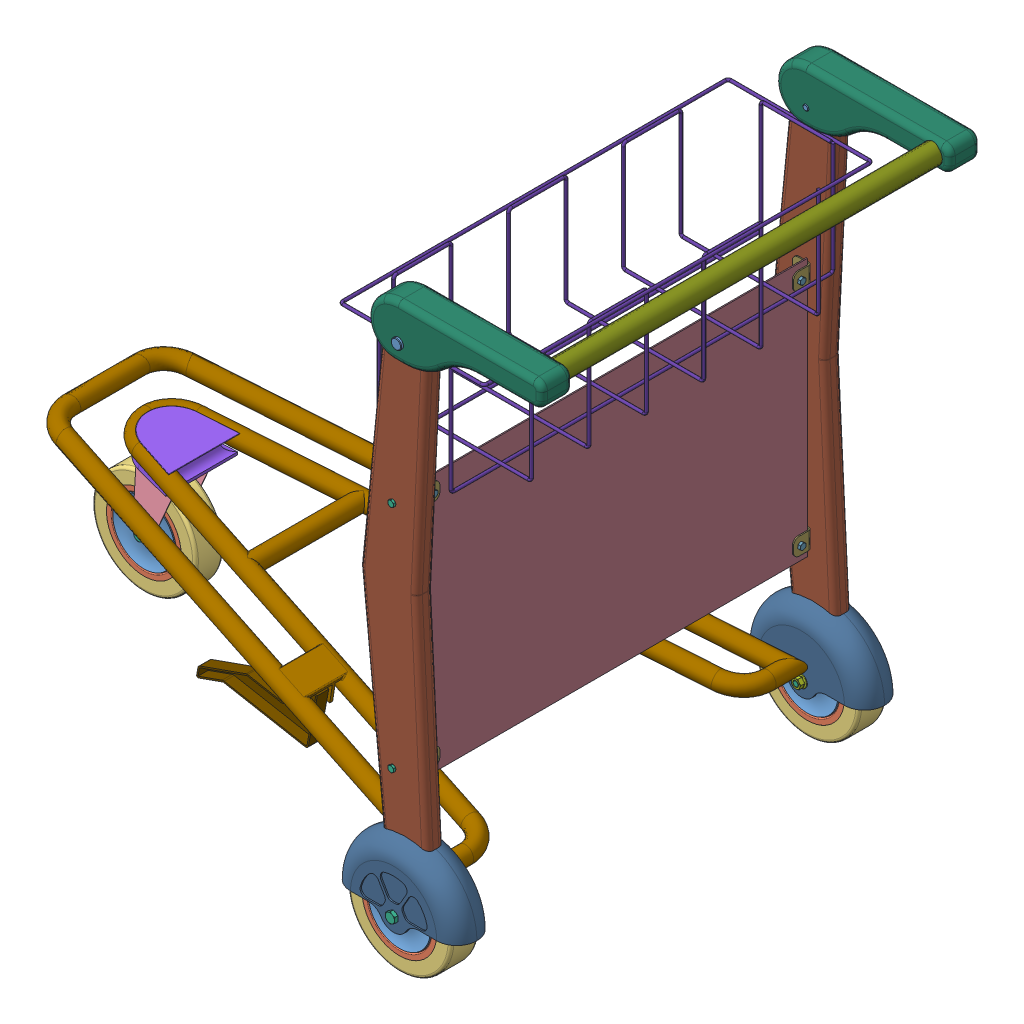
SolidWorks assembly Airport Trolley, configuration Default. Lengths in mm.
Overall size (1159.66 1012.5 792.8).
66 component instances, 19 part files, 94 mates.
Components (placement in the parent):
- Castor With Bracket-1: Castor With Bracket [Default] at origin size (180 254.25 124.91)
  - Castor Wheel-1: Castor Wheel [Default] at origin size (180 180 79.3)
    - Inside 2-1: Inside 2 [Default] at origin size (110.08 110.08 79.3)
    - Inside 1-1: Inside 1 [Default] at origin size (130 130 50)
    - Rubber Wheel-2: Rubber Wheel [Default] at (0 45 25) x (0 0 1) z (-1 0 0) size (50 180 180)
  - Castor Bracket-1: Castor Bracket [Default] at (-10.2542 104.2118 25) x (0 0 -1) z (-0.060111 -0.998192 0) size (56.48 71.04 113.41)
  - Bracket Top-1: Bracket Top [Default] at (28.7861 104.684 17.6727) x (0.060111 0.998192 0) z (0 0 1) size (15 52 52)
  - hex bolt gradeab_iso-1: hex bolt gradeab_iso [ISO 4014 - M10 x 70 x 26-C] at (0 0 59.6369) x (0 0 -1) z (1 0 0) size (76.4 18.48 16)
  - hex flange nut gradea_iso-2: hex flange nut gradea_iso [Hexagon Flange Nut ISO - 4161 - M10 - N] at (0 0 -13.2369) x (0.923728 0.383049 0) z (0 0 -1) size (21.8 21.8 10)
  - Rubber Top-1: Rubber Top [Default] at (80.9125 134.2079 90) x (-0.989154 0.146881 0) z (0 0 -1) size (106.47 44.76 124.91)
- Luggage Frame-2: Luggage Frame [Default<As Machined>] at (793.1035 28.4538 320) x (-0.989154 0.146881 0) z (0 0 -1) size (942.05 35.85 636.5)
- Back Wheel-2: Back Wheel [Default] at (795 0 350) size (220 200 86.4)
  - Castor Wheel-1: Castor Wheel [Default] at origin size (180 180 79.3)
    - Inside 2-1: Inside 2 [Default] at origin size (110.08 110.08 79.3)
    - Inside 1-1: Inside 1 [Default] at origin size (130 130 50)
    - Rubber Wheel-2: Rubber Wheel [Default] at (0 45 25) x (0 0 1) z (-1 0 0) size (50 180 180)
  - Wheel Casing-1: Wheel Casing [Default] at (0 0 -10) size (220 135 70)
  - hex bolt gradeab_iso-1: hex bolt gradeab_iso [ISO 4014 - M10 x 80 x 26-C] at (0 0 66.4) x (0 0 -1) z (1 0 0) size (86.4 18.48 16)
  - hex flange nut gradea_iso-1: hex flange nut gradea_iso [Hexagon Flange Nut ISO - 4161 - M10 - N] at (0 0 -20) x (0.923728 0.383049 0) z (0 0 -1) size (21.8 21.8 10)
- Back Wheel-3: Back Wheel [Default] at (795 0 -310) x (-1 0 0) z (0 0 -1) size (220 200 86.4)
  - Castor Wheel-1: Castor Wheel [Default] at origin size (180 180 79.3)
    - Inside 2-1: Inside 2 [Default] at origin size (110.08 110.08 79.3)
    - Inside 1-1: Inside 1 [Default] at origin size (130 130 50)
    - Rubber Wheel-2: Rubber Wheel [Default] at (0 45 25) x (0 0 1) z (-1 0 0) size (50 180 180)
  - Wheel Casing-1: Wheel Casing [Default] at (0 0 -10) size (220 135 70)
  - hex bolt gradeab_iso-1: hex bolt gradeab_iso [ISO 4014 - M10 x 80 x 26-C] at (0 0 66.4) x (0 0 -1) z (1 0 0) size (86.4 18.48 16)
  - hex flange nut gradea_iso-1: hex flange nut gradea_iso [Hexagon Flange Nut ISO - 4161 - M10 - N] at (0 0 -20) x (0.923728 0.383049 0) z (0 0 -1) size (21.8 21.8 10)
- Support-1: Support [Right] at (835 80 -320) x (-1 0 0) z (0 0 -1) size (119.95 779.01 31.28)
- Support-3: Support [Left] at (835 80 390) x (-1 0 0) z (0 0 -1) size (119.95 779.01 31.28)
- 'L' Bracket-1: 'L' Bracket [Default] at (791.3545 602.9093 -320) x (1 0 0) z (0 -1 0) size (32.07 32.07 30)
- 'L' Bracket-2: 'L' Bracket [Default] at (791.3545 202.9093 -320) x (1 0 0) z (0 -1 0) size (32.07 32.07 30)
- 'L' Bracket-3: 'L' Bracket [Default] at (791.3545 602.9093 360) x (1 0 0) z (0 1 0) size (32.07 32.07 30)
- 'L' Bracket-4: 'L' Bracket [Default] at (791.3545 202.9093 360) x (1 0 0) z (0 1 0) size (32.07 32.07 30)
- Advert Board-2: Advert Board [Default] at (789.4275 402.9093 20) x (0 0 -1) z (1 0 0) size (668 450 2)
- hex bolt gradeab_iso-7: hex bolt gradeab_iso [ISO 4014 - M6 x 40 x 18-N] at (773.8545 602.9093 394) x (0 0 -1) z (1 0 0) size (44 11.55 10)
- hex bolt gradeab_iso-8: hex bolt gradeab_iso [ISO 4014 - M6 x 40 x 18-N] at (773.8545 202.9093 394) x (0 0 -1) z (1 0 0) size (44 11.55 10)
- hex bolt gradeab_iso-9: hex bolt gradeab_iso [ISO 4014 - M6 x 40 x 18-N] at (773.8545 202.9093 -354) x (0 0 1) z (-1 0 0) size (44 11.55 10)
- hex bolt gradeab_iso-10: hex bolt gradeab_iso [ISO 4014 - M6 x 40 x 18-N] at (773.8545 602.9093 -354) x (0 0 1) z (-1 0 0) size (44 11.55 10)
- hex flange nut gradea_iso-2: hex flange nut gradea_iso [Hexagon Flange Nut ISO - 4161 - M6 - N] at (773.8545 602.9093 352) x (0.923728 0.383049 0) z (0 0 -1) size (14.2 14.2 6)
- hex flange nut gradea_iso-3: hex flange nut gradea_iso [Hexagon Flange Nut ISO - 4161 - M6 - N] at (773.8545 202.9093 352) x (0.923728 0.383049 0) z (0 0 -1) size (14.2 14.2 6)
- hex flange nut gradea_iso-4: hex flange nut gradea_iso [Hexagon Flange Nut ISO - 4161 - M6 - N] at (773.8545 202.9093 -312) size (14.2 14.2 6)
- hex flange nut gradea_iso-5: hex flange nut gradea_iso [Hexagon Flange Nut ISO - 4161 - M6 - N] at (773.8545 602.9093 -312) size (14.2 14.2 6)
- hex screw gradec_iso-1: hex screw gradec_iso [ISO 4018 - M6 x 12-NN] at (797.8025 602.9093 -300.427) x (-1 0 0) z (0 0.924225 0.381849) size (16.38 11.55 10)
- hex screw gradec_iso-2: hex screw gradec_iso [ISO 4018 - M6 x 12-NN] at (797.8025 602.9093 340.427) x (-1 0 0) z (0 0.924225 0.381849) size (16.38 11.55 10)
- hex screw gradec_iso-3: hex screw gradec_iso [ISO 4018 - M6 x 12-NN] at (797.8025 202.9093 340.427) x (-1 0 0) z (0 0.924225 0.381849) size (16.38 11.55 10)
- hex screw gradec_iso-4: hex screw gradec_iso [ISO 4018 - M6 x 12-NN] at (797.8025 202.9093 -300.427) x (-1 0 0) z (0 0.924225 0.381849) size (16.38 11.55 10)
- hex flange nut gradea_iso-6: hex flange nut gradea_iso [Hexagon Flange Nut ISO - 4161 - M6 - N] at (783.4275 602.9093 340.427) x (0 0 1) z (-1 0 0) size (14.2 14.2 6)
- hex flange nut gradea_iso-7: hex flange nut gradea_iso [Hexagon Flange Nut ISO - 4161 - M6 - N] at (783.4275 602.9093 -300.427) x (0 0 1) z (-1 0 0) size (14.2 14.2 6)
- hex flange nut gradea_iso-8: hex flange nut gradea_iso [Hexagon Flange Nut ISO - 4161 - M6 - N] at (783.4275 202.9093 -300.427) x (0 0 1) z (-1 0 0) size (14.2 14.2 6)
- hex flange nut gradea_iso-9: hex flange nut gradea_iso [Hexagon Flange Nut ISO - 4161 - M6 - N] at (783.4275 202.9093 340.427) x (0 0 1) z (-1 0 0) size (14.2 14.2 6)
- Handle-1: Handle [Right] at (795.0187 860 -308) x (-1 0 0) z (0 0 -1) size (303.42 93.75 54)
- Handle-3: Handle [Left] at (795.0187 860 402) x (-1 0 0) z (0 0 -1) size (303.42 93.75 54)
- Handle Bar-1: Handle Bar [Default] at (1015.0187 900.625 20) size (34 34 744)
- Basket-1: Basket [Default] at (775 826 20) x (0 0 1) z (-1 0 0) size (680 200 255)
- Lock-1: Lock [Right] at (472.1076 75.5835 -160) x (-0.983426 0.181312 0) z (0 0 -1) size (193.3 113.17 20)
- Lock-2: Lock [Left] at (472.1076 75.5835 220) x (-0.983426 0.181312 0) z (0 0 -1) size (193.3 113.17 20)
- clevis pin headed_iso-1: clevis pin headed_iso [Clevis Pin ISO 2341 - B - 10 x 55 - St] at (795.0187 860 -366) x (0 0 1) z (-1 0 0) size (59 18 18)
- clevis pin headed_iso-2: clevis pin headed_iso [Clevis Pin ISO 2341 - B - 10 x 55 - St] at (795.0187 860 406) x (0 0 -1) z (1 0 0) size (59 18 18)
- hex screw gradec_iso-5: hex screw gradec_iso [ISO 4018 - M5 x 12-NC] at (455.5431 68.4689 -166.375) x (0 0 1) z (-1 0 0) size (15.88 9.24 8)
- hex screw gradec_iso-6: hex screw gradec_iso [ISO 4018 - M5 x 12-NC] at (435.8746 72.0951 -166.375) x (0 0 1) z (-1 0 0) size (15.88 9.24 8)
- hex screw gradec_iso-7: hex screw gradec_iso [ISO 4018 - M5 x 12-NC] at (455.5431 68.4689 206.375) x (0 0 -1) z (1 0 0) size (15.88 9.24 8)
- hex screw gradec_iso-8: hex screw gradec_iso [ISO 4018 - M5 x 12-NC] at (435.8746 72.0951 206.375) x (0 0 -1) z (1 0 0) size (15.88 9.24 8)
- hex flange nut gradea_iso-10: hex flange nut gradea_iso [Hexagon Flange Nut ISO - 4161 - M5 - C] at (435.8746 72.0951 -150) size (11.8 11.8 5)
- hex flange nut gradea_iso-11: hex flange nut gradea_iso [Hexagon Flange Nut ISO - 4161 - M5 - C] at (455.5431 68.4689 -150) size (11.8 11.8 5)
- hex flange nut gradea_iso-12: hex flange nut gradea_iso [Hexagon Flange Nut ISO - 4161 - M5 - C] at (435.76 71.4065 190) x (0.923728 0.383049 0) z (0 0 -1) size (11.8 11.8 5)
- hex flange nut gradea_iso-13: hex flange nut gradea_iso [Hexagon Flange Nut ISO - 4161 - M5 - C] at (455.5431 68.4689 190) x (0.923728 0.383049 0) z (0 0 -1) size (11.8 11.8 5)
Mates (geometry in assembly coordinates):
- Coincident7: coincident: plane of Castor With Bracket-1/Rubber Top-1 through (80.9125 134.2079 90) normal (0.146881 0.989154 0); plane of Luggage Frame-2 through (793.1035 28.4538 320) normal (0.146881 0.989154 0)
- Distance9: distance = 720 mm: plane of Castor With Bracket-1/Rubber Top-1 through (80.9125 134.2079 90) normal (-0.989154 0.146881 0); plane of Luggage Frame-2 through (793.1035 28.4538 320) normal (-0.989154 0.146881 0)
- Distance10: distance = 230 mm: plane of Castor With Bracket-1/Rubber Top-1 through (80.9125 134.2079 90) normal (0 0 -1); plane of Luggage Frame-2 through (793.1035 28.4538 320) normal (0 0 -1)
- Distance12: distance = 350 mm: plane of ? through (0 0 0) normal (0 0 1); plane of ? through (795 0 350) normal (0 0 1)
- Coincident12: coincident: plane of ? through (0 0 0) normal (0 1 0); plane of ? through (795 0 350) normal (0 1 0)
- Distance11: distance = 795 mm: plane of ? through (0 0 0) normal (1 0 0); plane of ? through (795 0 350) normal (1 0 0)
- Distance14: distance = 310 mm: plane of ? through (0 0 0) normal (0 0 1); plane of ? through (795 0 -310) normal (0 0 -1)
- Coincident15: coincident: plane of ? through (0 0 0) normal (0 1 0); plane of ? through (795 0 -310) normal (0 1 0)
- Distance13: distance = 795 mm: plane of ? through (0 0 0) normal (1 0 0); plane of ? through (795 0 -310) normal (-1 0 0)
- Distance15: distance = 10 mm: plane of ? through (795 0 -310) normal (0 0 -1); plane of Support-1 through (835 80 -320) normal (0 0 -1)
- Distance16: distance = 80 mm: plane of ? through (795 0 -310) normal (0 1 0); plane of Support-1 through (835 80 -320) normal (0 1 0)
- Distance17: distance = 40 mm: plane of ? through (795 0 -310) normal (-1 0 0); plane of Support-1 through (835 80 -320) normal (-1 0 0)
- Distance21: distance = 40 mm: plane of ? through (795 0 350) normal (0 0 1); plane of Support-3 through (835 80 390) normal (0 0 -1)
- Distance22: distance = 80 mm: plane of ? through (795 0 350) normal (0 1 0); plane of Support-3 through (835 80 390) normal (0 1 0)
- Distance23: distance = 40 mm: plane of ? through (795 0 350) normal (1 0 0); plane of Support-3 through (835 80 390) normal (-1 0 0)
- Coincident19: coincident: cylinder of Support-1 through (773.8545 602.9093 -350.6717) axis (0 0 1) radius 3; circle of 'L' Bracket-1
- Coincident20: coincident: plane of Support-1 through (835 80 -320) normal (0 0 1); plane of 'L' Bracket-1 through (771.3545 607.9093 -320) normal (0 0 -1)
- Coincident23: coincident: cylinder of Support-1 through (773.8545 202.9093 -350.6717) axis (0 0 1) radius 3; circle of 'L' Bracket-2
- Coincident24: coincident: plane of Support-1 through (835 80 -320) normal (0 0 1); plane of 'L' Bracket-2 through (771.3545 207.9093 -320) normal (0 0 -1)
- Coincident25: coincident: cylinder of Support-3 through (773.8545 602.9093 390.6095) axis (0 0 -1) radius 3; circle of 'L' Bracket-3
- Coincident26: coincident: plane of Support-3 through (835 80 360) normal (0 0 -1); plane of 'L' Bracket-3 through (771.3545 597.9093 360) normal (0 0 1)
- Coincident27: coincident: cylinder of Support-3 through (773.8545 202.9093 390.6095) axis (0 0 -1) radius 3; circle of 'L' Bracket-4
- Coincident28: coincident: plane of Support-3 through (835 80 360) normal (0 0 -1); plane of 'L' Bracket-4 through (771.3545 197.9093 360) normal (0 0 1)
- Coincident33: coincident: plane of Advert Board-2 through (791.4275 627.9093 354) normal (1 0 0); plane of 'L' Bracket-3 through (791.4275 597.9093 377.927) normal (-1 0 0)
- Distance24: distance = 4 mm: plane of 'L' Bracket-3 through (771.3545 597.9093 358) normal (0 0 -1); plane of Advert Board-2 through (791.4275 177.9093 354) normal (0 0 1)
- Distance25: distance = 10 mm: plane of 'L' Bracket-3 through (791.4275 617.9093 377.927) normal (0 1 0); plane of Advert Board-2 through (791.4275 627.9093 -314) normal (0 1 0)
- Concentric6: concentric: cylinder of Support-3 through (773.8545 602.9093 390.6095) axis (0 0 -1) radius 3; cylinder of hex bolt gradeab_iso-7 through (773.8545 602.9093 394) axis (0 0 1) radius 5
- Coincident41: coincident: plane of Support-3 through (835 80 390) normal (0 0 1); plane of hex bolt gradeab_iso-7 through (773.8545 608.6828 390) normal (0 0 -1)
- Concentric7: concentric: cylinder of Support-3 through (773.8545 202.9093 390.6095) axis (0 0 -1) radius 3; cylinder of hex bolt gradeab_iso-8 through (773.8545 202.9093 394) axis (0 0 1) radius 5
- Coincident42: coincident: plane of Support-3 through (835 80 390) normal (0 0 1); plane of hex bolt gradeab_iso-8 through (773.8545 208.6828 390) normal (0 0 -1)
- Concentric8: concentric: cylinder of Support-1 through (773.8545 202.9093 -350.6717) axis (0 0 1) radius 3; cylinder of hex bolt gradeab_iso-9 through (773.8545 202.9093 -354) axis (0 0 -1) radius 5
- Coincident43: coincident: plane of Support-1 through (835 80 -350) normal (0 0 -1); plane of hex bolt gradeab_iso-9 through (773.8545 208.6828 -350) normal (0 0 1)
- Concentric9: concentric: cylinder of Support-1 through (773.8545 602.9093 -350.6717) axis (0 0 1) radius 3; cylinder of hex bolt gradeab_iso-10 through (773.8545 602.9093 -354) axis (0 0 -1) radius 5
- Coincident44: coincident: plane of Support-1 through (835 80 -350) normal (0 0 -1); plane of hex bolt gradeab_iso-10 through (773.8545 608.6828 -350) normal (0 0 1)
- Concentric10: concentric: cylinder of 'L' Bracket-3 through (773.8545 602.9093 358) axis (0 0 -1) radius 3; cylinder of hex flange nut gradea_iso-2 through (773.8545 602.9093 377.0375) axis (0 0 -1) radius 3
- Coincident45: coincident: plane of 'L' Bracket-3 through (771.3545 597.9093 358) normal (0 0 -1); plane of hex flange nut gradea_iso-2 through (776.0661 597.5762 358) normal (0 0 1)
- Concentric11: concentric: cylinder of 'L' Bracket-4 through (773.8545 202.9093 358) axis (0 0 -1) radius 3; cylinder of hex flange nut gradea_iso-3 through (773.8545 202.9093 377.0375) axis (0 0 -1) radius 3
- Coincident46: coincident: plane of 'L' Bracket-4 through (771.3545 197.9093 358) normal (0 0 -1); plane of hex flange nut gradea_iso-3 through (776.0661 197.5762 358) normal (0 0 1)
- Concentric12: concentric: cylinder of 'L' Bracket-2 through (773.8545 202.9093 -318) axis (0 0 1) radius 3; cylinder of hex flange nut gradea_iso-4 through (773.8545 202.9093 -337.0375) axis (0 0 1) radius 3
- Coincident47: coincident: plane of 'L' Bracket-2 through (771.3545 207.9093 -318) normal (0 0 1); plane of hex flange nut gradea_iso-4 through (773.8545 208.6828 -318) normal (0 0 -1)
- Concentric13: concentric: cylinder of 'L' Bracket-1 through (773.8545 602.9093 -318) axis (0 0 1) radius 3; cylinder of hex flange nut gradea_iso-5 through (773.8545 602.9093 -337.0375) axis (0 0 1) radius 3
- Coincident48: coincident: plane of 'L' Bracket-1 through (771.3545 607.9093 -318) normal (0 0 1); plane of hex flange nut gradea_iso-5 through (773.8545 608.6828 -318) normal (0 0 -1)
- Concentric14: concentric: cylinder of 'L' Bracket-1 through (791.4275 602.9093 -300.427) axis (-1 0 0) radius 3; cylinder of hex screw gradec_iso-1 through (797.8025 602.9093 -300.427) axis (1 0 0) radius 3
- Coincident49: coincident: plane of 'L' Bracket-1 through (793.4275 607.9093 -337.927) normal (1 0 0); plane of hex screw gradec_iso-1 through (793.4275 600.7047 -295.091) normal (-1 0 0)
- Concentric15: concentric: cylinder of 'L' Bracket-3 through (791.4275 602.9093 340.427) axis (-1 0 0) radius 3; cylinder of hex screw gradec_iso-2 through (797.8025 602.9093 340.427) axis (1 0 0) radius 3
- Coincident50: coincident: plane of 'L' Bracket-3 through (793.4275 597.9093 377.927) normal (1 0 0); plane of hex screw gradec_iso-2 through (793.4275 600.7047 345.763) normal (-1 0 0)
- Concentric16: concentric: cylinder of 'L' Bracket-4 through (791.4275 202.9093 340.427) axis (-1 0 0) radius 3; cylinder of hex screw gradec_iso-3 through (797.8025 202.9093 340.427) axis (1 0 0) radius 3
- Coincident51: coincident: plane of 'L' Bracket-4 through (793.4275 197.9093 377.927) normal (1 0 0); plane of hex screw gradec_iso-3 through (793.4275 200.7047 345.763) normal (-1 0 0)
- Concentric171: concentric: cylinder of 'L' Bracket-2 through (791.4275 202.9093 -300.427) axis (-1 0 0) radius 3; cylinder of hex screw gradec_iso-4 through (797.8025 202.9093 -300.427) axis (1 0 0) radius 3
- Coincident521: coincident: plane of 'L' Bracket-2 through (793.4275 207.9093 -337.927) normal (1 0 0); plane of hex screw gradec_iso-4 through (793.4275 200.7047 -295.091) normal (-1 0 0)
- Concentric18: concentric: cylinder of hex screw gradec_iso-2 through (797.8025 602.9093 340.427) axis (1 0 0) radius 3; cylinder of hex flange nut gradea_iso-6 through (808.465 602.9093 340.427) axis (-1 0 0) radius 3
- Coincident53: coincident: plane of Advert Board-2 through (789.4275 627.9093 354) normal (-1 0 0); plane of hex flange nut gradea_iso-6 through (789.4275 608.6828 340.427) normal (1 0 0)
- Concentric19: concentric: cylinder of hex screw gradec_iso-1 through (797.8025 602.9093 -300.427) axis (1 0 0) radius 3; cylinder of hex flange nut gradea_iso-7 through (808.465 602.9093 -300.427) axis (-1 0 0) radius 3
- Coincident54: coincident: plane of Advert Board-2 through (789.4275 627.9093 354) normal (-1 0 0); plane of hex flange nut gradea_iso-7 through (789.4275 608.6828 -300.427) normal (1 0 0)
- Concentric20: concentric: cylinder of hex screw gradec_iso-4 through (797.8025 202.9093 -300.427) axis (1 0 0) radius 3; cylinder of hex flange nut gradea_iso-8 through (808.465 202.9093 -300.427) axis (-1 0 0) radius 3
- Coincident55: coincident: plane of Advert Board-2 through (789.4275 627.9093 354) normal (-1 0 0); plane of hex flange nut gradea_iso-8 through (789.4275 208.6828 -300.427) normal (1 0 0)
- Concentric21: concentric: cylinder of hex screw gradec_iso-3 through (797.8025 202.9093 340.427) axis (1 0 0) radius 3; cylinder of hex flange nut gradea_iso-9 through (808.465 202.9093 340.427) axis (-1 0 0) radius 3
- Coincident56: coincident: plane of Advert Board-2 through (789.4275 627.9093 354) normal (-1 0 0); plane of hex flange nut gradea_iso-9 through (789.4275 208.6828 340.427) normal (1 0 0)
- Coincident522: coincident: cylinder of Support-1 through (795.0187 860 -319.3905) axis (0 0 -1) radius 5; circle of Handle-1
- Distance26: distance = 2 mm: plane of Support-1 through (835 80 -350) normal (0 0 -1); plane of Handle-1 through (795.0187 860 -352) normal (0 0 1)
- Parallel1: parallel: plane of Support-1 through (835 80 -320) normal (0 1 0); plane of Handle-1 through (795.0187 860 -308) normal (0 1 0)
- Coincident530: coincident: cylinder of Support-3 through (795.0187 860 390.6095) axis (0 0 -1) radius 5; circle of Handle-3
- Distance27: distance = 2 mm: plane of Support-3 through (835 80 360) normal (0 0 -1); plane of Handle-3 through (795.0187 860 358) normal (0 0 1)
- Parallel3: parallel: plane of Support-3 through (835 80 390) normal (0 1 0); plane of Handle-3 through (795.0187 860 402) normal (0 1 0)
- Concentric172: concentric: cylinder of Handle-1 through (1015.0187 900.625 -318) axis (0 0 1) radius 17.5; circle of Handle Bar-1
- Coincident533: coincident: plane of Handle-3 through (795.0187 860 392) normal (0 0 -1); plane of Handle Bar-1 through (1015.0187 900.625 392) normal (0 0 1)
- Distance29: distance = 60 mm: plane of Support-3 through (835 80 390) normal (-1 0 0); plane of Basket-1 through (775 826 20) normal (-1 0 0)
- Distance30: distance = 746 mm: plane of Support-3 through (835 80 390) normal (0 1 0); plane of Basket-1 through (775 826 20) normal (0 1 0)
- Distance31: distance = 370 mm: plane of Support-3 through (835 80 390) normal (0 0 -1); plane of Basket-1 through (775 826 20) normal (0 0 1)
- Concentric173: concentric: cylinder of Handle-1 through (795.0187 860 -308) axis (0 0 -1) radius 5; cylinder of clevis pin headed_iso-1 through (795.0187 860 -366) axis (0 0 -1) radius 9
- Coincident534: coincident: plane of Handle-1 through (795.0187 860 -362) normal (0 0 -1); plane of clevis pin headed_iso-1 through (795.0187 869 -362) normal (0 0 1)
- Concentric174: concentric: cylinder of Handle-3 through (795.0187 860 402) axis (0 0 -1) radius 5; cylinder of clevis pin headed_iso-2 through (795.0187 860 406) axis (0 0 1) radius 9
- Coincident535: coincident: plane of Handle-3 through (795.0187 860 402) normal (0 0 1); plane of clevis pin headed_iso-2 through (795.0187 869 402) normal (0 0 -1)
- Coincident536: coincident: cylinder of Luggage Frame-2 through (455.5431 68.4689 338.2476) axis (0 0 -1) radius 2.5; circle of Lock-1
- Coincident537: coincident: cylinder of Luggage Frame-2 through (455.5431 68.4689 338.2476) axis (0 0 -1) radius 2.5; circle of Lock-1
- Coincident538: coincident: plane of Luggage Frame-2 through (473.8574 55.6397 -160) normal (0 0 -1); plane of Lock-1 through (334.5529 -134.7837 -160) normal (0 0 1)
- Coincident539: coincident: cylinder of Luggage Frame-2 through (455.5431 68.4689 -298.2526) axis (0 0 1) radius 2.5; circle of Lock-2
- Coincident540: coincident: plane of Luggage Frame-2 through (473.8574 55.6397 200) normal (0 0 1); plane of Lock-2 through (334.5529 -134.7837 200) normal (0 0 -1)
- Concentric175: concentric: cylinder of Lock-1 through (455.5431 68.4689 -160) axis (0 0 -1) radius 2.5; cylinder of hex screw gradec_iso-5 through (455.5431 68.4689 -166.375) axis (0 0 -1) radius 2.5
- Coincident541: coincident: plane of Lock-1 through (334.5529 -134.7837 -162.5) normal (0 0 -1); plane of hex screw gradec_iso-5 through (455.5431 73.0877 -162.5) normal (0 0 1)
- Concentric176: concentric: cylinder of Lock-1 through (435.8746 72.0951 -160) axis (0 0 -1) radius 2.5; cylinder of hex screw gradec_iso-6 through (435.8746 72.0951 -166.375) axis (0 0 -1) radius 2.5
- Coincident542: coincident: plane of Lock-1 through (334.5529 -134.7837 -162.5) normal (0 0 -1); plane of hex screw gradec_iso-6 through (435.8746 76.7139 -162.5) normal (0 0 1)
- Concentric177: concentric: cylinder of Lock-2 through (455.5431 68.4689 200) axis (0 0 1) radius 2.5; cylinder of hex screw gradec_iso-7 through (455.5431 68.4689 206.375) axis (0 0 1) radius 2.5
- Coincident543: coincident: plane of Lock-2 through (334.5529 -134.7837 202.5) normal (0 0 1); plane of hex screw gradec_iso-7 through (455.5431 73.0877 202.5) normal (0 0 -1)
- Concentric178: concentric: cylinder of Lock-2 through (435.8746 72.0951 200) axis (0 0 1) radius 2.5; cylinder of hex screw gradec_iso-8 through (435.8746 72.0951 206.375) axis (0 0 1) radius 2.5
- Coincident544: coincident: plane of Lock-2 through (334.5529 -134.7837 202.5) normal (0 0 1); plane of hex screw gradec_iso-8 through (435.8746 76.7139 202.5) normal (0 0 -1)
- Concentric179: concentric: cylinder of hex screw gradec_iso-6 through (435.8746 72.0951 -166.375) axis (0 0 -1) radius 2.5; cylinder of hex flange nut gradea_iso-10 through (435.8746 72.0951 -175.0375) axis (0 0 1) radius 2.5
- Coincident545: coincident: plane of Luggage Frame-2 through (473.8574 55.6397 -155) normal (0 0 1); plane of hex flange nut gradea_iso-10 through (427.8746 72.0951 -155) normal (0 0 -1)
- Concentric180: concentric: cylinder of hex screw gradec_iso-5 through (455.5431 68.4689 -166.375) axis (0 0 -1) radius 2.5; cylinder of hex flange nut gradea_iso-11 through (455.5431 68.4689 -175.0375) axis (0 0 1) radius 2.5
- Coincident546: coincident: plane of Luggage Frame-2 through (473.8574 55.6397 -155) normal (0 0 1); plane of hex flange nut gradea_iso-11 through (447.5431 68.4689 -155) normal (0 0 -1)
- Concentric181: concentric: cylinder of Luggage Frame-2 through (435.76 71.4065 -298.2526) axis (0 0 1) radius 2.5; cylinder of hex flange nut gradea_iso-12 through (435.76 71.4065 215.0375) axis (0 0 -1) radius 2.5
- Coincident547: coincident: plane of Luggage Frame-2 through (473.8574 55.6397 195) normal (0 0 -1); plane of hex flange nut gradea_iso-12 through (428.3702 68.3421 195) normal (0 0 1)
- Concentric182: concentric: cylinder of Luggage Frame-2 through (455.5431 68.4689 -298.2526) axis (0 0 1) radius 2.5; cylinder of hex flange nut gradea_iso-13 through (455.5431 68.4689 215.0375) axis (0 0 -1) radius 2.5
- Coincident548: coincident: plane of Luggage Frame-2 through (473.8574 55.6397 195) normal (0 0 -1); plane of hex flange nut gradea_iso-13 through (448.1533 65.4045 195) normal (0 0 1)
